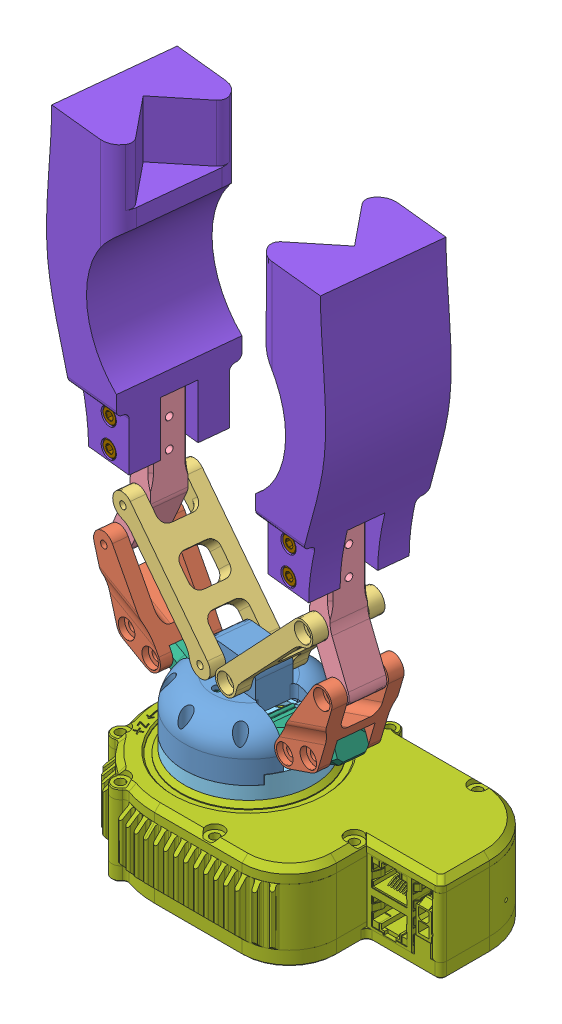
SolidWorks assembly Gripper, configuration Default. Lengths in mm.
Overall size (132.13 195.81 73.14).
23 component instances, 9 part files, 20 mates.
Components (placement in the parent):
- Hebi Motor with Gripper-1: Hebi Motor with Gripper [Default] at (-48.6457 -21.5594 3.9658) size (128.79 124.31 73.14)
  - HEBI Robotics-A-2143-02-1: HEBI Robotics-A-2143-02 [Default] at (0 4.6253 0) x (0.994658 0 0.103227) z (-0.103227 0 0.994658) size (112.08 105.21 45) (flexible)
    - HEBI Robotics-A-2143-02_PM-2357-02-1: HEBI Robotics-A-2143-02_PM-2357-02 [Default] at (0 30.9247 0) x (0 0 -1) z (1 0 0) size (45 28 44.67)
    - HEBI Robotics-A-2143-02_PM-2358-02-1: HEBI Robotics-A-2143-02_PM-2358-02 [Default] at (-30.4569 31.8574 0) x (0 0 -1) z (0.926102 -0.377274 0) size (23 26 33)
    - HEBI Robotics-A-2143-02_PM-2358-02-2: HEBI Robotics-A-2143-02_PM-2358-02 [Default] at (30.456 31.8595 0) x (0 0 1) z (-0.926098 -0.377283 0) size (23 26 33)
    - HEBI Robotics-A-2143-02_PM-2359-02-1: HEBI Robotics-A-2143-02_PM-2359-02 [Default] at (20.1262 54.8052 0) x (0 0 1) z (0.689702 0.724093 0) size (23 8 51.86)
    - HEBI Robotics-A-2143-02_PM-2359-02-2: HEBI Robotics-A-2143-02_PM-2359-02 [Default] at (-20.1272 54.8043 0) x (0 0 -1) z (-0.689746 0.724052 0) size (23 8 51.86)
    - HEBI Robotics-A-2143-02_PM-2360-02-1: HEBI Robotics-A-2143-02_PM-2360-02 [Default] at (-35.2543 70.6838 0) x (-1 -0.000026 0) z (0 0 -1) size (15.5 54 12.08)
    - HEBI Robotics-A-2143-02_PM-2360-02-2: HEBI Robotics-A-2143-02_PM-2360-02 [Default] at (35.2524 70.6856 0) x (1 0.000026 0) z (0 0 1) size (15.5 54 12.08)
    - HEBI Robotics-A-2055-01_PM-2218-01-1: HEBI Robotics-A-2055-01_PM-2218-01 [Default] at (0 11.4247 0) size (45 32.5 45)
    - HEBI Robotics-A-2055-01_PM-2221-01-1: HEBI Robotics-A-2055-01_PM-2221-01 [Default] at (12.5 22.9247 0) x (0.926098 0.377283 0) z (0 0 1) size (35.49 9.86 12)
    - HEBI Robotics-A-2055-01_PM-2221-01-2: HEBI Robotics-A-2055-01_PM-2221-01 [Default] at (-12.5 22.9247 0) x (-0.926154 0.377146 0) z (0 0 -1) size (35.49 9.86 12)
  - HEBI Robotics-X5-Export-2021-1: HEBI Robotics-X5-Export-2021 [Default] x (1 0 0) z (0 1 0) size (109.71 73.14 31.05)
- gripper finger-1: gripper finger [Default] at (-55.6003 119.2497 -16.8634) x (0.994658 0 0.103227) z (0 -1 0) size (29.91 40 90)
- gripper finger-2: gripper finger [Default] at (-41.6945 119.2515 24.7946) x (-0.994658 0 -0.103227) z (0 -1 0) size (29.91 40 90)
- 91292A114_M3-0.5x12-1: 91292A114_M3-0.5x12 [91292A114] at (-83.795 82.7497 1.1223) x (-0.922369 -0.374262 -0.095725) z (0.103227 0 -0.994658) size (5.5 5.5 15.23)
- 91292A114_M3-0.5x12-2: 91292A114_M3-0.5x12 [91292A114] at (-83.795 72.7497 1.1223) x (-0.860402 -0.501733 -0.089294) z (0.103227 0 -0.994658) size (5.5 5.5 15.23)
- 91292A114_M3-0.5x12-4: 91292A114_M3-0.5x12 [91292A114] at (-83.6299 82.7497 -0.4692) x (-0.122616 -0.992373 -0.012725) z (-0.103227 0 0.994658) size (5.5 5.5 15.23)
- 91292A114_M3-0.5x12-6: 91292A114_M3-0.5x12 [91292A114] at (-83.6299 72.7497 -0.4692) x (0.056962 -0.998359 0.005912) z (-0.103227 0 0.994658) size (5.5 5.5 15.23)
- 91292A114_M3-0.5x12-8: 91292A114_M3-0.5x12 [91292A114] at (-13.4998 82.7515 6.809) x (0.237271 -0.971131 0.024624) z (-0.103227 0 0.994658) size (5.5 5.5 15.23)
- 91292A114_M3-0.5x12-10: 91292A114_M3-0.5x12 [91292A114] at (-13.4998 72.7515 6.809) x (0.411818 -0.910263 0.042739) z (-0.103227 0 0.994658) size (5.5 5.5 15.23)
- 91292A114_M3-0.5x12-12: 91292A114_M3-0.5x12 [91292A114] at (-13.6649 82.7515 8.4005) x (-0.731519 -0.677582 -0.075918) z (0.103227 0 -0.994658) size (5.5 5.5 15.23)
- 91292A114_M3-0.5x12-14: 91292A114_M3-0.5x12 [91292A114] at (-13.6649 72.7515 8.4005) x (-0.785512 -0.613453 -0.081522) z (0.103227 0 -0.994658) size (5.5 5.5 15.23)
Mates (geometry in assembly coordinates):
- Width1: width anti-aligned: plane of gripper finger-1 through (-59.3165 119.2497 18.9443) normal (-0.103227 0 0.994658); plane of gripper finger-1 through (-56.0132 119.2497 -12.8847) normal (0.103227 0 -0.994658); plane of Hebi Motor with Gripper-1/HEBI Robotics-A-2143-02-1/HEBI Robotics-A-2143-02_PM-2360-02-1 through (-90.5519 37.7495 -6.4155) normal (0.103227 0 -0.994658); plane of Hebi Motor with Gripper-1/HEBI Robotics-A-2143-02-1/HEBI Robotics-A-2143-02_PM-2360-02-1 through (-91.7906 37.7495 5.5204) normal (-0.103227 0 0.994658)
- Width2: width anti-aligned: plane of gripper finger-2 through (-41.2816 119.2515 20.816) normal (-0.103227 0 0.994658); plane of gripper finger-2 through (-37.9783 119.2515 -11.013) normal (0.103227 0 -0.994658); plane of Hebi Motor with Gripper-1/HEBI Robotics-A-2143-02-1/HEBI Robotics-A-2143-02_PM-2360-02-2 through (-5.5019 37.7517 2.4111) normal (0.103227 0 -0.994658); plane of Hebi Motor with Gripper-1/HEBI Robotics-A-2143-02-1/HEBI Robotics-A-2143-02_PM-2360-02-2 through (-6.7406 37.7517 14.347) normal (-0.103227 0 0.994658)
- Concentric1: concentric aligned: cylinder of Hebi Motor with Gripper-1/HEBI Robotics-A-2143-02-1/HEBI Robotics-A-2143-02_PM-2360-02-1 through (-84.3318 82.7497 6.2945) axis (-0.103227 0 0.994658) radius 1.25; cylinder of gripper finger-1 through (-81.6479 82.7497 -19.5666) axis (-0.103227 0 0.994658) radius 1.75
- Concentric2: concentric aligned: cylinder of Hebi Motor with Gripper-1/HEBI Robotics-A-2143-02-1/HEBI Robotics-A-2143-02_PM-2360-02-2 through (-12.963 82.7515 1.6368) axis (0.103227 0 -0.994658) radius 1.25; cylinder of gripper finger-2 through (-15.6469 82.7515 27.4979) axis (0.103227 0 -0.994658) radius 1.75
- Coincident1: coincident anti-aligned: plane of gripper finger-1 through (-85.0337 82.7497 13.0582) normal (-0.103227 0 0.994658); plane of 91292A114_M3-0.5x12-1 through (-85.0337 82.7497 13.0582) normal (0.103227 0 -0.994658)
- Concentric3: concentric anti-aligned: cylinder of gripper finger-1 through (-85.0337 82.7497 13.0582) axis (-0.103227 0 0.994658) radius 3; cylinder of 91292A114_M3-0.5x12-1 through (-85.3434 82.7497 16.0421) axis (0.103227 0 -0.994658) radius 2.75
- Coincident2: coincident anti-aligned: plane of gripper finger-1 through (-85.0337 72.7497 13.0582) normal (-0.103227 0 0.994658); plane of 91292A114_M3-0.5x12-2 through (-85.0337 72.7497 13.0582) normal (0.103227 0 -0.994658)
- Concentric4: concentric anti-aligned: cylinder of gripper finger-1 through (-85.0337 72.7497 13.0582) axis (-0.103227 0 0.994658) radius 3; cylinder of 91292A114_M3-0.5x12-2 through (-85.3434 72.7497 16.0421) axis (0.103227 0 -0.994658) radius 2.75
- Coincident3: coincident anti-aligned: plane of gripper finger-1 through (-82.3911 82.7497 -12.4051) normal (0.103227 0 -0.994658); plane of 91292A114_M3-0.5x12-4 through (-82.3911 82.7497 -12.4051) normal (-0.103227 0 0.994658)
- Concentric5: concentric anti-aligned: cylinder of gripper finger-1 through (-82.3911 82.7497 -12.4051) axis (0.103227 0 -0.994658) radius 3; cylinder of 91292A114_M3-0.5x12-4 through (-82.0815 82.7497 -15.3891) axis (-0.103227 0 0.994658) radius 2.75
- Coincident4: coincident anti-aligned: plane of gripper finger-1 through (-82.3911 72.7497 -12.4051) normal (0.103227 0 -0.994658); plane of 91292A114_M3-0.5x12-6 through (-82.3911 72.7497 -12.4051) normal (-0.103227 0 0.994658)
- Concentric6: concentric anti-aligned: cylinder of gripper finger-1 through (-82.3911 72.7497 -12.4051) axis (0.103227 0 -0.994658) radius 3; cylinder of 91292A114_M3-0.5x12-6 through (-82.0815 72.7497 -15.3891) axis (-0.103227 0 0.994658) radius 2.75
- Coincident5: coincident anti-aligned: plane of gripper finger-2 through (-12.2611 82.7515 -5.1269) normal (0.103227 0 -0.994658); plane of 91292A114_M3-0.5x12-8 through (-12.2611 82.7515 -5.1269) normal (-0.103227 0 0.994658)
- Concentric7: concentric anti-aligned: cylinder of gripper finger-2 through (-12.2611 82.7515 -5.1269) axis (0.103227 0 -0.994658) radius 3; cylinder of 91292A114_M3-0.5x12-8 through (-11.9514 82.7515 -8.1109) axis (-0.103227 0 0.994658) radius 2.75
- Coincident6: coincident anti-aligned: plane of gripper finger-2 through (-12.2611 72.7515 -5.1269) normal (0.103227 0 -0.994658); plane of 91292A114_M3-0.5x12-10 through (-12.2611 72.7515 -5.1269) normal (-0.103227 0 0.994658)
- Concentric8: concentric anti-aligned: cylinder of gripper finger-2 through (-12.2611 72.7515 -5.1269) axis (0.103227 0 -0.994658) radius 3; cylinder of 91292A114_M3-0.5x12-10 through (-11.9514 72.7515 -8.1109) axis (-0.103227 0 0.994658) radius 2.75
- Coincident7: coincident anti-aligned: plane of gripper finger-2 through (-14.9037 82.7515 20.3364) normal (-0.103227 0 0.994658); plane of 91292A114_M3-0.5x12-12 through (-14.9037 82.7515 20.3364) normal (0.103227 0 -0.994658)
- Concentric9: concentric anti-aligned: cylinder of gripper finger-2 through (-14.9037 82.7515 20.3364) axis (-0.103227 0 0.994658) radius 3; cylinder of 91292A114_M3-0.5x12-12 through (-15.2133 82.7515 23.3203) axis (0.103227 0 -0.994658) radius 2.75
- Coincident8: coincident anti-aligned: plane of gripper finger-2 through (-14.9037 72.7515 20.3364) normal (-0.103227 0 0.994658); plane of 91292A114_M3-0.5x12-14 through (-14.9037 72.7515 20.3364) normal (0.103227 0 -0.994658)
- Concentric10: concentric anti-aligned: cylinder of gripper finger-2 through (-14.9037 72.7515 20.3364) axis (-0.103227 0 0.994658) radius 3; cylinder of 91292A114_M3-0.5x12-14 through (-15.2133 72.7515 23.3203) axis (0.103227 0 -0.994658) radius 2.75
